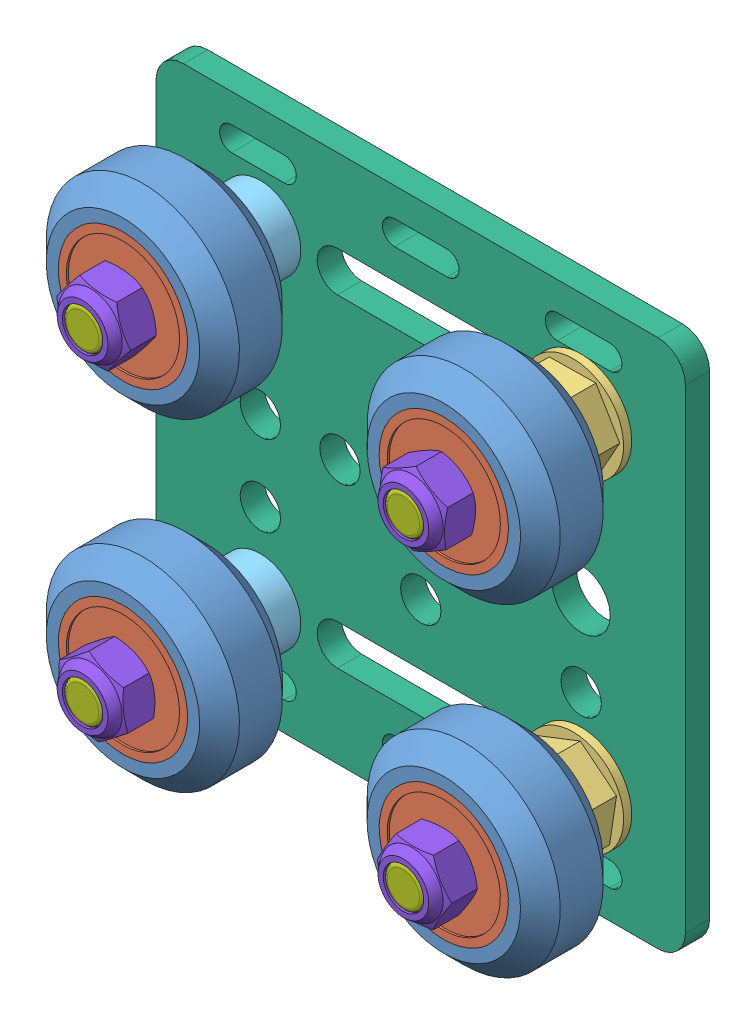
SolidWorks assembly 20mm Gantry Set, configuration Default. Lengths in mm.
Overall size (71.69 71.99 27).
34 component instances, 8 part files, 0 mates.
Components (placement in the parent):
- 20mm Gantry Set.stp-1: 20mm Gantry Set.stp [Default] at origin size (71.69 71.99 27)
  - V-Wheel Solid Wheel.stp-1: V-Wheel Solid Wheel.stp [Default] at (31.4376 30.3864 0.786) x (0.859314 0.511448 0) z (0.511448 -0.859314 0) size (23.9 20 23.9)
    - Solid V-Wheel.stp-1: Solid V-Wheel.stp [Default] at (-15.2695 -5.901 2.9988) size (23.9 10.23 23.9)
    - Ball Bearing 625 2RS 5x16x5.stp-1: Ball Bearing 625 2RS 5x16x5.stp [Default] at (-15.2695 -5.671 2.9988) x (1 0 0) z (0 1 0) size (16 16 5)
    - Ball Bearing 625 2RS 5x16x5.stp-2: Ball Bearing 625 2RS 5x16x5.stp [Default] at (-15.2695 -0.671 2.9988) x (0.579467 0 0.814996) z (0 1 0) size (16 16 5)
    - Eccentric Spacer.stp-1: Eccentric Spacer.stp [Default] at (-15.2695 -6.671 2.9988) x (1 0 0) z (0 -1 0) size (12.5 12.5 9)
    - 1mm 5mm shim.stp-1: 1mm 5mm shim.stp [Default] at (-15.2695 -5.671 2.9988) x (1 0 0) z (0 -1 0) size (10 10 1)
  - V-Wheel Solid Wheel.stp-2: V-Wheel Solid Wheel.stp [Default] at (28.1904 -33.1373 0.786) x (0.363236 -0.931697 0) z (-0.931697 -0.363236 0) size (23.9 20 23.9)
    - Solid V-Wheel.stp-1: Solid V-Wheel.stp [Default] at (-15.2695 -5.901 2.9988) size (23.9 10.23 23.9)
    - Ball Bearing 625 2RS 5x16x5.stp-1: Ball Bearing 625 2RS 5x16x5.stp [Default] at (-15.2695 -5.671 2.9988) x (1 0 0) z (0 1 0) size (16 16 5)
    - Ball Bearing 625 2RS 5x16x5.stp-2: Ball Bearing 625 2RS 5x16x5.stp [Default] at (-15.2695 -0.671 2.9988) x (0.579467 0 0.814996) z (0 1 0) size (16 16 5)
    - Eccentric Spacer.stp-1: Eccentric Spacer.stp [Default] at (-15.2695 -6.671 2.9988) x (1 0 0) z (0 -1 0) size (12.5 12.5 9)
    - 1mm 5mm shim.stp-1: 1mm 5mm shim.stp [Default] at (-15.2695 -5.671 2.9988) x (1 0 0) z (0 -1 0) size (10 10 1)
  - V-Wheel Solid Wheel - spacer.stp-1: V-Wheel Solid Wheel - spacer.stp [Default] at (-4.4084 21.9251 0.786) x (0.997558 -0.069836 0) z (-0.069836 -0.997558 0) size (23.9 17 23.9)
    - Solid V-Wheel.stp-1: Solid V-Wheel.stp [Default] at (-15.2695 -5.901 2.9988) size (23.9 10.23 23.9)
    - Ball Bearing 625 2RS 5x16x5.stp-1: Ball Bearing 625 2RS 5x16x5.stp [Default] at (-15.2695 -5.671 2.9988) x (1 0 0) z (0 1 0) size (16 16 5)
    - Ball Bearing 625 2RS 5x16x5.stp-2: Ball Bearing 625 2RS 5x16x5.stp [Default] at (-15.2695 -0.671 2.9988) x (0.579467 0 0.814996) z (0 1 0) size (16 16 5)
    - 1mm 5mm shim.stp-1: 1mm 5mm shim.stp [Default] at (-15.2695 -5.671 2.9988) x (1 0 0) z (0 -1 0) size (10 10 1)
    - 6mm Spacer.stp-1: 6mm Spacer.stp [Default] at (-15.2695 -6.671 2.9988) x (1 0 0) z (0 -1 0) size (10 10 6)
  - V-Wheel Solid Wheel - spacer.stp-2: V-Wheel Solid Wheel - spacer.stp [Default] at (-6.8841 -11.3956 0.786) x (0.92416 0.382005 0) z (0.382005 -0.92416 0) size (23.9 17 23.9)
    - Solid V-Wheel.stp-1: Solid V-Wheel.stp [Default] at (-15.2695 -5.901 2.9988) size (23.9 10.23 23.9)
    - Ball Bearing 625 2RS 5x16x5.stp-1: Ball Bearing 625 2RS 5x16x5.stp [Default] at (-15.2695 -5.671 2.9988) x (1 0 0) z (0 1 0) size (16 16 5)
    - Ball Bearing 625 2RS 5x16x5.stp-2: Ball Bearing 625 2RS 5x16x5.stp [Default] at (-15.2695 -0.671 2.9988) x (0.579467 0 0.814996) z (0 1 0) size (16 16 5)
    - 1mm 5mm shim.stp-1: 1mm 5mm shim.stp [Default] at (-15.2695 -5.671 2.9988) x (1 0 0) z (0 -1 0) size (10 10 1)
    - 6mm Spacer.stp-1: 6mm Spacer.stp [Default] at (-15.2695 -6.671 2.9988) x (1 0 0) z (0 -1 0) size (10 10 6)
  - 20mm gantry plate.stp-1: 20mm gantry plate.stp [Default] at (0 0 -14.885) size (65.5 65.5 3)
  - M5x25 low profile screw.stp-1: M5x25 low profile screw.stp [Default] at (19.85 -20 -16.885) x (0.999998 -0.001827 0) z (0 0 1) size (11 11 27)
  - M5x25 low profile screw.stp-2: M5x25 low profile screw.stp [Default] at (19.85 20 -16.885) x (1 0.000182 0) z (0 0 1) size (11 11 27)
  - M5x25 low profile screw.stp-3: M5x25 low profile screw.stp [Default] at (-19.85 -20 -16.885) x (0.999594 -0.02849 0) z (0 0 1) size (11 11 27)
  - M5 Nylock.stp-1: M5 Nylock.stp [Default] at (19.85 -20 5.115) x (-0.864363 0.502868 0) z (0 0 1) size (9.24 9.25 5)
  - M5 Nylock.stp-2: M5 Nylock.stp [Default] at (19.85 20 5.115) x (0.463993 -0.885839 0) z (0 0 1) size (9.24 9.25 5)
  - M5 Nylock.stp-3: M5 Nylock.stp [Default] at (-19.85 20 5.115) x (-0.135333 -0.9908 0) z (0 0 1) size (9.24 9.25 5)
  - M5 Nylock.stp-4: M5 Nylock.stp [Default] at (-19.85 -20 5.115) x (-0.99254 -0.121918 0) z (0 0 1) size (9.24 9.25 5)
  - M5x25 low profile screw.stp-4: M5x25 low profile screw.stp [Default] at (-19.85 20 -16.885) x (1 0.000026 0) z (0 0 1) size (11 11 27)
